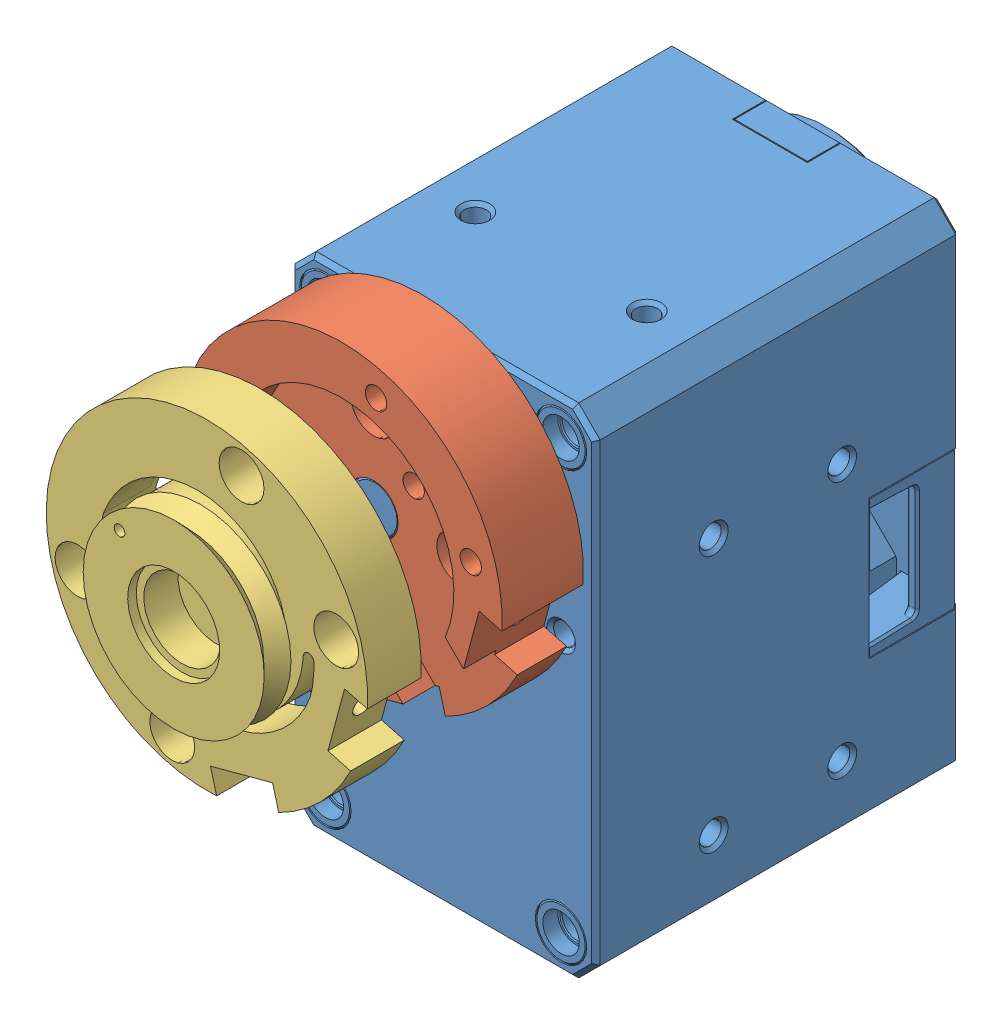
SolidWorks assembly SEA_v2, configuration 기본. Lengths in mm.
Overall size (42.43 56.46 61.16).
4 component instances, 4 part files, 9 mates.
Components (placement in the parent):
- xm-430_idle(stp)-1: xm-430_idle(stp) [기본] at (58.9604 9.1289 -2.2) size (28.5 46.5 42.4)
- SEA_motor_v5-1: SEA_motor_v5 [기본] at (58.9604 9.1289 16.7) size (30 30 7.6)
- SEA_pulley_v7_part2-1: SEA_pulley_v7_part2 [기본] at (58.9604 9.1289 31.8585) x (0.707107 0.707107 0) z (0 0 1) size (30 30 8.1)
- SEA_shaft-1: SEA_shaft [기본] at (58.9604 9.1289 35.4) x (-0.707107 -0.707107 0) z (0 0 -1) size (21.62 21.83 19.7) (hidden)
Mates (geometry in assembly coordinates):
- 동심1: concentric anti-aligned: cylinder of xm-430_idle(stp)-1 through (58.9604 9.1289 18.7) axis (0 0 1) radius 2.25; cylinder of SEA_motor_v5-1 through (58.9604 9.1289 21.3) axis (0 0 -1) radius 2.3
- 일치1: coincident anti-aligned: plane of xm-430_idle(stp)-1 through (58.9604 9.1289 18.7) normal (0 0 1); plane of SEA_motor_v5-1 through (58.9604 9.1289 18.7) normal (0 0 -1)
- 동심2: concentric aligned: cylinder of xm-430_idle(stp)-1 through (66.9604 9.1289 14.1953) axis (0 0 1) radius 0.8; cylinder of SEA_motor_v5-1 through (66.9604 9.1289 10.7603) axis (0 0 1) radius 2.1
- 동심3: concentric aligned: cylinder of SEA_motor_v5-1 through (58.9604 9.1289 21.3) axis (0 0 -1) radius 15; cylinder of SEA_pulley_v7_part2-1 through (58.9604 9.1289 33.2585) axis (0 0 -1) radius 15
- 일치2: coincident aligned: plane of SEA_motor_v5-1 through (71.8109 8.7915 24.3) normal (0.965926 -0.258819 0); plane of SEA_pulley_v7_part2-1 through (70.258 2.9959 31.8585) normal (0.965926 -0.258819 0)
- 일치4: coincident anti-aligned: plane of SEA_motor_v5-1 through (58.9604 9.1289 24.3) normal (0 0 1); plane of SEA_pulley_v7_part2-1 through (58.9604 9.1289 24.3) normal (0 0 -1)
- 동심4: concentric anti-aligned: cylinder of SEA_pulley_v7_part2-1 through (58.9604 9.1289 33.2585) axis (0 0 -1) radius 15; cylinder of SEA_shaft-1 through (58.9604 9.1289 36.4) axis (0 0 1) radius 6
- 일치6: coincident aligned: plane of SEA_motor_v5-1 through (58.9604 9.1289 16.7) normal (0 0 -1); plane of SEA_shaft-1 through (58.9604 9.1289 16.7) normal (0 0 -1)
- 동심5: concentric aligned: cylinder of SEA_pulley_v7_part2-1 through (61.678 -1.0133 26.8) axis (0.258819 -0.965926 0) radius 0.95; cylinder of SEA_shaft-1 through (56.2164 19.3696 26.8) axis (0.258819 -0.965926 0) radius 1.2
